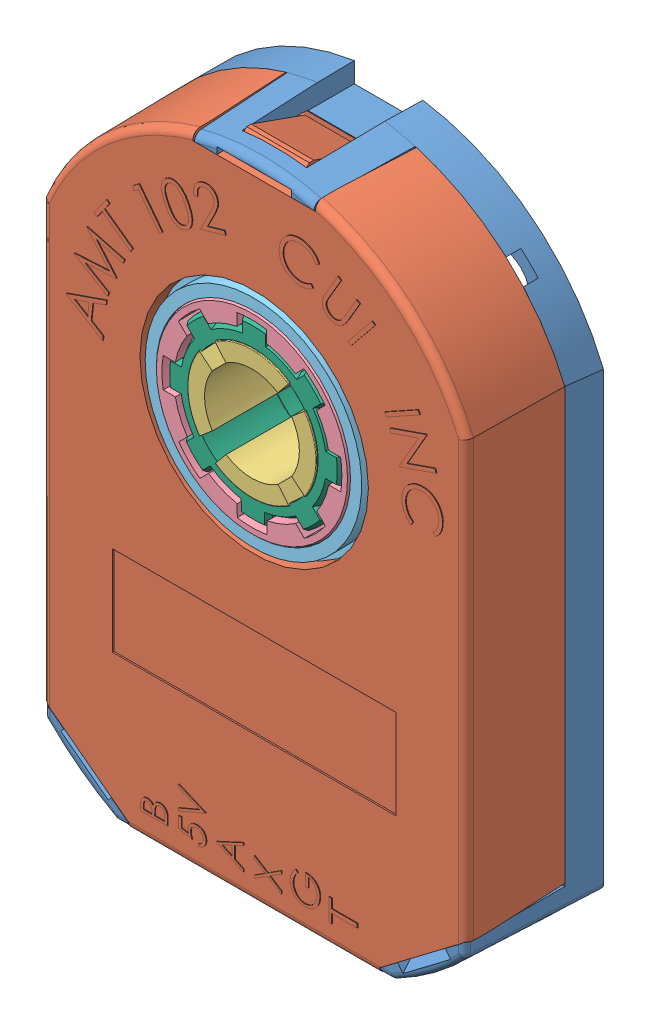
SolidWorks assembly AARL_QR_EL_EN2-amt102-0048-i6350-s, configuration Default. Lengths in mm.
Overall size (36.33 46.23 9.15).
9 component instances, 9 part files, 0 mates.
Components (placement in the parent):
- AARL_QR_EL_EN2_001-CUI_DEVICES_amt-102-base-rev-k-1: AARL_QR_EL_EN2_001-CUI_DEVICES_amt-102-base-rev-k [Default] x (-1 0 0) z (0 0 -1) size (28.83 43.41 9.03)
- AARL_QR_EL_EN2_002-CUI_DEVICES_amt-102-top-cover-rev-h-1: AARL_QR_EL_EN2_002-CUI_DEVICES_amt-102-top-cover-rev-h [Default] at (0 0 5.23) x (-1 0 0) z (0 0 -1) size (28.6 43.26 6.55)
- AARL_QR_EL_EN2_003-CUI_DEVICES_amt-sleeve-rev-d(d)-1: AARL_QR_EL_EN2_003-CUI_DEVICES_amt-sleeve-rev-d(d) [Default] at (0 0 -2.42) x (0.999996 0.002864 0) z (0 0 1) size (10.79 10.79 7.8)
- AARL_QR_EL_EN2_004-CUI_DEVICES_amt-hub-top-rev-d1-1: AARL_QR_EL_EN2_004-CUI_DEVICES_amt-hub-top-rev-d1 [Default] at (0 0 2.13) x (0.999996 0.002864 0) z (0 0 1) size (14 14 5.67)
- AARL_QR_EL_EN2_005-CUI_DEVICES_amt-hub-bottom-rev-b-1: AARL_QR_EL_EN2_005-CUI_DEVICES_amt-hub-bottom-rev-b [Default] at (0 0 2.43) x (0.999998 -0.001942 0) z (0 0 1) size (17.3 17.3 3.2)
- AARL_QR_EL_EN2_006-CUI_DEVICES_amt10x-shaft-adaptor-rev-e-1: AARL_QR_EL_EN2_006-CUI_DEVICES_amt10x-shaft-adaptor-rev-e [Default] at (0 0 0.03) x (0.999996 0.002864 0) z (0 0 1) size (11.8 11.8 7.8)
- AARL_QR_EL_EN2_007-CUI_DEVICES_receiver-board-1: AARL_QR_EL_EN2_007-CUI_DEVICES_receiver-board [Default] at (72.2834 -20.351 3.03) x (-1 0 0) z (0 0 -1) size (26.5 26.62 0.41)
- AARL_QR_EL_EN2_008-CUI_DEVICES_rotor-board-rev f-1: AARL_QR_EL_EN2_008-CUI_DEVICES_rotor-board-rev f [Default] at (0 0 2.13) x (0.807874 -0.589355 0) z (0 0 1) size (26 26 0.3)
- AARL_QR_EL_EN2_009-CUI_DEVICES_transmitter-board amt10(amt-102)-1: AARL_QR_EL_EN2_009-CUI_DEVICES_transmitter-board amt10(amt-102) [Default] at (19.1596 -17.1102 1.22) x (-1 0 0) z (0 0 -1) size (26.63 38.43 4.41)
